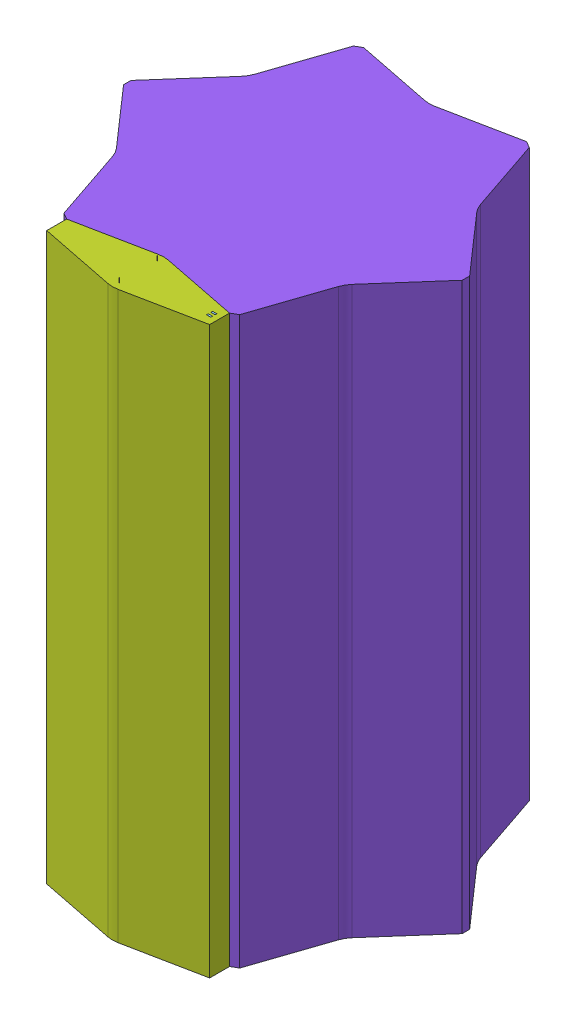
SolidWorks assembly String-Array, configuration 默认. Lengths in mm.
Overall size (790 1330.46 891.35).
243 component instances, 8 part files, 4 mates.
Components (placement in the parent):
- RealString-1: RealString [默认] at (506.9717 -579.0791 1993.5225) size (380 1330.46 350.65)
  - RealUnit-1: RealUnit [默认] at origin size (374.87 90.61 350.65)
    - BEGeDet-1: BEGeDet [默认] at (2.9686 -23.0613 80) size (80 40 80)
    - InnerShell-IV-1: InnerShell-IV [默认] at (2.9686 -23.1113 80) x (0.656103 0 0.754671) z (-0.754671 0 0.656103) size (90 50 90)
    - RealOuterShell-IV-Part-3: RealOuterShell-IV-Part [默认] at (2.9686 -24.1113 80) x (-1 0 0) z (0 0 -1) size (357.21 73.56 262.25)
    - RealOuterShell-IV-Part-4: RealOuterShell-IV-Part [默认] at (2.5967 -24.1114 80) x (1 0.000332 0) z (0 0 1) size (357.21 73.56 262.25)
    - Electronics-1: Electronics [默认] at (2.9686 -48.2113 80) x (-1 0 0) z (0 0 -1) size (21.21 85 89.7)
    - ConnectionUnit-1: ConnectionUnit [默认] at (157.8605 -24.8554 155) x (-1 -0.000332 0) z (0 0 -1) size (23 75 26.4)
      - ConnectionRod-IV-1: ConnectionRod-IV [默认] at (-16.742 6.238 75) size (23 75 14)
      - RealSiPMArray-1: RealSiPMArray [默认] at (-11.242 1.238 75) x (-1 0 0) z (0 0 -1) size (3.97 70 26.4)
    - ConnectionUnit-2: ConnectionUnit [默认] at (-152.295 -24.9069 5) size (23 75 26.4)
      - ConnectionRod-IV-1: ConnectionRod-IV [默认] at (-16.742 6.238 75) size (23 75 14)
      - RealSiPMArray-1: RealSiPMArray [默认] at (-11.242 1.238 75) x (-1 0 0) z (0 0 -1) size (3.97 70 26.4)
  - RealUnit-2: RealUnit [默认] at (0 65 0) size (374.87 90.61 350.65)
    - BEGeDet-1: BEGeDet [默认] at (2.9686 -23.0613 80) size (80 40 80)
    - InnerShell-IV-1: InnerShell-IV [默认] at (2.9686 -23.1113 80) x (0.656103 0 0.754671) z (-0.754671 0 0.656103) size (90 50 90)
    - RealOuterShell-IV-Part-3: RealOuterShell-IV-Part [默认] at (2.9686 -24.1113 80) x (-1 0 0) z (0 0 -1) size (357.21 73.56 262.25)
    - RealOuterShell-IV-Part-4: RealOuterShell-IV-Part [默认] at (2.5967 -24.1114 80) x (1 0.000332 0) z (0 0 1) size (357.21 73.56 262.25)
    - Electronics-1: Electronics [默认] at (2.9686 -48.2113 80) x (-1 0 0) z (0 0 -1) size (21.21 85 89.7)
    - ConnectionUnit-1: ConnectionUnit [默认] at (157.8605 -24.8554 155) x (-1 -0.000332 0) z (0 0 -1) size (23 75 26.4)
      - ConnectionRod-IV-1: ConnectionRod-IV [默认] at (-16.742 6.238 75) size (23 75 14)
      - RealSiPMArray-1: RealSiPMArray [默认] at (-11.242 1.238 75) x (-1 0 0) z (0 0 -1) size (3.97 70 26.4)
    - ConnectionUnit-2: ConnectionUnit [默认] at (-152.295 -24.9069 5) size (23 75 26.4)
      - ConnectionRod-IV-1: ConnectionRod-IV [默认] at (-16.742 6.238 75) size (23 75 14)
      - RealSiPMArray-1: RealSiPMArray [默认] at (-11.242 1.238 75) x (-1 0 0) z (0 0 -1) size (3.97 70 26.4)
  - RealUnit-3: RealUnit [默认] at (0 130 0) size (374.87 90.61 350.65)
    - BEGeDet-1: BEGeDet [默认] at (2.9686 -23.0613 80) size (80 40 80)
    - InnerShell-IV-1: InnerShell-IV [默认] at (2.9686 -23.1113 80) x (0.656103 0 0.754671) z (-0.754671 0 0.656103) size (90 50 90)
    - RealOuterShell-IV-Part-3: RealOuterShell-IV-Part [默认] at (2.9686 -24.1113 80) x (-1 0 0) z (0 0 -1) size (357.21 73.56 262.25)
    - RealOuterShell-IV-Part-4: RealOuterShell-IV-Part [默认] at (2.5967 -24.1114 80) x (1 0.000332 0) z (0 0 1) size (357.21 73.56 262.25)
    - Electronics-1: Electronics [默认] at (2.9686 -48.2113 80) x (-1 0 0) z (0 0 -1) size (21.21 85 89.7)
    - ConnectionUnit-1: ConnectionUnit [默认] at (157.8605 -24.8554 155) x (-1 -0.000332 0) z (0 0 -1) size (23 75 26.4)
      - ConnectionRod-IV-1: ConnectionRod-IV [默认] at (-16.742 6.238 75) size (23 75 14)
      - RealSiPMArray-1: RealSiPMArray [默认] at (-11.242 1.238 75) x (-1 0 0) z (0 0 -1) size (3.97 70 26.4)
    - ConnectionUnit-2: ConnectionUnit [默认] at (-152.295 -24.9069 5) size (23 75 26.4)
      - ConnectionRod-IV-1: ConnectionRod-IV [默认] at (-16.742 6.238 75) size (23 75 14)
      - RealSiPMArray-1: RealSiPMArray [默认] at (-11.242 1.238 75) x (-1 0 0) z (0 0 -1) size (3.97 70 26.4)
  - RealUnit-4: RealUnit [默认] at (0 195 0) size (374.87 90.61 350.65)
    - BEGeDet-1: BEGeDet [默认] at (2.9686 -23.0613 80) size (80 40 80)
    - InnerShell-IV-1: InnerShell-IV [默认] at (2.9686 -23.1113 80) x (0.656103 0 0.754671) z (-0.754671 0 0.656103) size (90 50 90)
    - RealOuterShell-IV-Part-3: RealOuterShell-IV-Part [默认] at (2.9686 -24.1113 80) x (-1 0 0) z (0 0 -1) size (357.21 73.56 262.25)
    - RealOuterShell-IV-Part-4: RealOuterShell-IV-Part [默认] at (2.5967 -24.1114 80) x (1 0.000332 0) z (0 0 1) size (357.21 73.56 262.25)
    - Electronics-1: Electronics [默认] at (2.9686 -48.2113 80) x (-1 0 0) z (0 0 -1) size (21.21 85 89.7)
    - ConnectionUnit-1: ConnectionUnit [默认] at (157.8605 -24.8554 155) x (-1 -0.000332 0) z (0 0 -1) size (23 75 26.4)
      - ConnectionRod-IV-1: ConnectionRod-IV [默认] at (-16.742 6.238 75) size (23 75 14)
      - RealSiPMArray-1: RealSiPMArray [默认] at (-11.242 1.238 75) x (-1 0 0) z (0 0 -1) size (3.97 70 26.4)
    - ConnectionUnit-2: ConnectionUnit [默认] at (-152.295 -24.9069 5) size (23 75 26.4)
      - ConnectionRod-IV-1: ConnectionRod-IV [默认] at (-16.742 6.238 75) size (23 75 14)
      - RealSiPMArray-1: RealSiPMArray [默认] at (-11.242 1.238 75) x (-1 0 0) z (0 0 -1) size (3.97 70 26.4)
  - RealUnit-5: RealUnit [默认] at (0 260 0) size (374.87 90.61 350.65)
    - BEGeDet-1: BEGeDet [默认] at (2.9686 -23.0613 80) size (80 40 80)
    - InnerShell-IV-1: InnerShell-IV [默认] at (2.9686 -23.1113 80) x (0.656103 0 0.754671) z (-0.754671 0 0.656103) size (90 50 90)
    - RealOuterShell-IV-Part-3: RealOuterShell-IV-Part [默认] at (2.9686 -24.1113 80) x (-1 0 0) z (0 0 -1) size (357.21 73.56 262.25)
    - RealOuterShell-IV-Part-4: RealOuterShell-IV-Part [默认] at (2.5967 -24.1114 80) x (1 0.000332 0) z (0 0 1) size (357.21 73.56 262.25)
    - Electronics-1: Electronics [默认] at (2.9686 -48.2113 80) x (-1 0 0) z (0 0 -1) size (21.21 85 89.7)
    - ConnectionUnit-1: ConnectionUnit [默认] at (157.8605 -24.8554 155) x (-1 -0.000332 0) z (0 0 -1) size (23 75 26.4)
      - ConnectionRod-IV-1: ConnectionRod-IV [默认] at (-16.742 6.238 75) size (23 75 14)
      - RealSiPMArray-1: RealSiPMArray [默认] at (-11.242 1.238 75) x (-1 0 0) z (0 0 -1) size (3.97 70 26.4)
    - ConnectionUnit-2: ConnectionUnit [默认] at (-152.295 -24.9069 5) size (23 75 26.4)
      - ConnectionRod-IV-1: ConnectionRod-IV [默认] at (-16.742 6.238 75) size (23 75 14)
      - RealSiPMArray-1: RealSiPMArray [默认] at (-11.242 1.238 75) x (-1 0 0) z (0 0 -1) size (3.97 70 26.4)
  - RealUnit-6: RealUnit [默认] at (0 325 0) size (374.87 90.61 350.65)
    - BEGeDet-1: BEGeDet [默认] at (2.9686 -23.0613 80) size (80 40 80)
    - InnerShell-IV-1: InnerShell-IV [默认] at (2.9686 -23.1113 80) x (0.656103 0 0.754671) z (-0.754671 0 0.656103) size (90 50 90)
    - RealOuterShell-IV-Part-3: RealOuterShell-IV-Part [默认] at (2.9686 -24.1113 80) x (-1 0 0) z (0 0 -1) size (357.21 73.56 262.25)
    - RealOuterShell-IV-Part-4: RealOuterShell-IV-Part [默认] at (2.5967 -24.1114 80) x (1 0.000332 0) z (0 0 1) size (357.21 73.56 262.25)
    - Electronics-1: Electronics [默认] at (2.9686 -48.2113 80) x (-1 0 0) z (0 0 -1) size (21.21 85 89.7)
    - ConnectionUnit-1: ConnectionUnit [默认] at (157.8605 -24.8554 155) x (-1 -0.000332 0) z (0 0 -1) size (23 75 26.4)
      - ConnectionRod-IV-1: ConnectionRod-IV [默认] at (-16.742 6.238 75) size (23 75 14)
      - RealSiPMArray-1: RealSiPMArray [默认] at (-11.242 1.238 75) x (-1 0 0) z (0 0 -1) size (3.97 70 26.4)
    - ConnectionUnit-2: ConnectionUnit [默认] at (-152.295 -24.9069 5) size (23 75 26.4)
      - ConnectionRod-IV-1: ConnectionRod-IV [默认] at (-16.742 6.238 75) size (23 75 14)
      - RealSiPMArray-1: RealSiPMArray [默认] at (-11.242 1.238 75) x (-1 0 0) z (0 0 -1) size (3.97 70 26.4)
  - RealUnit-7: RealUnit [默认] at (0 390 0) size (374.87 90.61 350.65)
    - BEGeDet-1: BEGeDet [默认] at (2.9686 -23.0613 80) size (80 40 80)
    - InnerShell-IV-1: InnerShell-IV [默认] at (2.9686 -23.1113 80) x (0.656103 0 0.754671) z (-0.754671 0 0.656103) size (90 50 90)
    - RealOuterShell-IV-Part-3: RealOuterShell-IV-Part [默认] at (2.9686 -24.1113 80) x (-1 0 0) z (0 0 -1) size (357.21 73.56 262.25)
    - RealOuterShell-IV-Part-4: RealOuterShell-IV-Part [默认] at (2.5967 -24.1114 80) x (1 0.000332 0) z (0 0 1) size (357.21 73.56 262.25)
    - Electronics-1: Electronics [默认] at (2.9686 -48.2113 80) x (-1 0 0) z (0 0 -1) size (21.21 85 89.7)
    - ConnectionUnit-1: ConnectionUnit [默认] at (157.8605 -24.8554 155) x (-1 -0.000332 0) z (0 0 -1) size (23 75 26.4)
      - ConnectionRod-IV-1: ConnectionRod-IV [默认] at (-16.742 6.238 75) size (23 75 14)
      - RealSiPMArray-1: RealSiPMArray [默认] at (-11.242 1.238 75) x (-1 0 0) z (0 0 -1) size (3.97 70 26.4)
    - ConnectionUnit-2: ConnectionUnit [默认] at (-152.295 -24.9069 5) size (23 75 26.4)
      - ConnectionRod-IV-1: ConnectionRod-IV [默认] at (-16.742 6.238 75) size (23 75 14)
      - RealSiPMArray-1: RealSiPMArray [默认] at (-11.242 1.238 75) x (-1 0 0) z (0 0 -1) size (3.97 70 26.4)
  - RealUnit-8: RealUnit [默认] at (0 455 0) size (374.87 90.61 350.65)
    - BEGeDet-1: BEGeDet [默认] at (2.9686 -23.0613 80) size (80 40 80)
    - InnerShell-IV-1: InnerShell-IV [默认] at (2.9686 -23.1113 80) x (0.656103 0 0.754671) z (-0.754671 0 0.656103) size (90 50 90)
    - RealOuterShell-IV-Part-3: RealOuterShell-IV-Part [默认] at (2.9686 -24.1113 80) x (-1 0 0) z (0 0 -1) size (357.21 73.56 262.25)
    - RealOuterShell-IV-Part-4: RealOuterShell-IV-Part [默认] at (2.5967 -24.1114 80) x (1 0.000332 0) z (0 0 1) size (357.21 73.56 262.25)
    - Electronics-1: Electronics [默认] at (2.9686 -48.2113 80) x (-1 0 0) z (0 0 -1) size (21.21 85 89.7)
    - ConnectionUnit-1: ConnectionUnit [默认] at (157.8605 -24.8554 155) x (-1 -0.000332 0) z (0 0 -1) size (23 75 26.4)
      - ConnectionRod-IV-1: ConnectionRod-IV [默认] at (-16.742 6.238 75) size (23 75 14)
      - RealSiPMArray-1: RealSiPMArray [默认] at (-11.242 1.238 75) x (-1 0 0) z (0 0 -1) size (3.97 70 26.4)
    - ConnectionUnit-2: ConnectionUnit [默认] at (-152.295 -24.9069 5) size (23 75 26.4)
      - ConnectionRod-IV-1: ConnectionRod-IV [默认] at (-16.742 6.238 75) size (23 75 14)
      - RealSiPMArray-1: RealSiPMArray [默认] at (-11.242 1.238 75) x (-1 0 0) z (0 0 -1) size (3.97 70 26.4)
  - RealUnit-9: RealUnit [默认] at (0 520 0) size (374.87 90.61 350.65)
    - BEGeDet-1: BEGeDet [默认] at (2.9686 -23.0613 80) size (80 40 80)
    - InnerShell-IV-1: InnerShell-IV [默认] at (2.9686 -23.1113 80) x (0.656103 0 0.754671) z (-0.754671 0 0.656103) size (90 50 90)
    - RealOuterShell-IV-Part-3: RealOuterShell-IV-Part [默认] at (2.9686 -24.1113 80) x (-1 0 0) z (0 0 -1) size (357.21 73.56 262.25)
    - RealOuterShell-IV-Part-4: RealOuterShell-IV-Part [默认] at (2.5967 -24.1114 80) x (1 0.000332 0) z (0 0 1) size (357.21 73.56 262.25)
    - Electronics-1: Electronics [默认] at (2.9686 -48.2113 80) x (-1 0 0) z (0 0 -1) size (21.21 85 89.7)
    - ConnectionUnit-1: ConnectionUnit [默认] at (157.8605 -24.8554 155) x (-1 -0.000332 0) z (0 0 -1) size (23 75 26.4)
      - ConnectionRod-IV-1: ConnectionRod-IV [默认] at (-16.742 6.238 75) size (23 75 14)
      - RealSiPMArray-1: RealSiPMArray [默认] at (-11.242 1.238 75) x (-1 0 0) z (0 0 -1) size (3.97 70 26.4)
    - ConnectionUnit-2: ConnectionUnit [默认] at (-152.295 -24.9069 5) size (23 75 26.4)
      - ConnectionRod-IV-1: ConnectionRod-IV [默认] at (-16.742 6.238 75) size (23 75 14)
      - RealSiPMArray-1: RealSiPMArray [默认] at (-11.242 1.238 75) x (-1 0 0) z (0 0 -1) size (3.97 70 26.4)
  - RealUnit-10: RealUnit [默认] at (0 585 0) size (374.87 90.61 350.65)
    - BEGeDet-1: BEGeDet [默认] at (2.9686 -23.0613 80) size (80 40 80)
    - InnerShell-IV-1: InnerShell-IV [默认] at (2.9686 -23.1113 80) x (0.656103 0 0.754671) z (-0.754671 0 0.656103) size (90 50 90)
    - RealOuterShell-IV-Part-3: RealOuterShell-IV-Part [默认] at (2.9686 -24.1113 80) x (-1 0 0) z (0 0 -1) size (357.21 73.56 262.25)
    - RealOuterShell-IV-Part-4: RealOuterShell-IV-Part [默认] at (2.5967 -24.1114 80) x (1 0.000332 0) z (0 0 1) size (357.21 73.56 262.25)
    - Electronics-1: Electronics [默认] at (2.9686 -48.2113 80) x (-1 0 0) z (0 0 -1) size (21.21 85 89.7)
    - ConnectionUnit-1: ConnectionUnit [默认] at (157.8605 -24.8554 155) x (-1 -0.000332 0) z (0 0 -1) size (23 75 26.4)
      - ConnectionRod-IV-1: ConnectionRod-IV [默认] at (-16.742 6.238 75) size (23 75 14)
      - RealSiPMArray-1: RealSiPMArray [默认] at (-11.242 1.238 75) x (-1 0 0) z (0 0 -1) size (3.97 70 26.4)
    - ConnectionUnit-2: ConnectionUnit [默认] at (-152.295 -24.9069 5) size (23 75 26.4)
      - ConnectionRod-IV-1: ConnectionRod-IV [默认] at (-16.742 6.238 75) size (23 75 14)
      - RealSiPMArray-1: RealSiPMArray [默认] at (-11.242 1.238 75) x (-1 0 0) z (0 0 -1) size (3.97 70 26.4)
  - RealUnit-11: RealUnit [默认] at (0 650 0) size (374.87 90.61 350.65)
    - BEGeDet-1: BEGeDet [默认] at (2.9686 -23.0613 80) size (80 40 80)
    - InnerShell-IV-1: InnerShell-IV [默认] at (2.9686 -23.1113 80) x (0.656103 0 0.754671) z (-0.754671 0 0.656103) size (90 50 90)
    - RealOuterShell-IV-Part-3: RealOuterShell-IV-Part [默认] at (2.9686 -24.1113 80) x (-1 0 0) z (0 0 -1) size (357.21 73.56 262.25)
    - RealOuterShell-IV-Part-4: RealOuterShell-IV-Part [默认] at (2.5967 -24.1114 80) x (1 0.000332 0) z (0 0 1) size (357.21 73.56 262.25)
    - Electronics-1: Electronics [默认] at (2.9686 -48.2113 80) x (-1 0 0) z (0 0 -1) size (21.21 85 89.7)
    - ConnectionUnit-1: ConnectionUnit [默认] at (157.8605 -24.8554 155) x (-1 -0.000332 0) z (0 0 -1) size (23 75 26.4)
      - ConnectionRod-IV-1: ConnectionRod-IV [默认] at (-16.742 6.238 75) size (23 75 14)
      - RealSiPMArray-1: RealSiPMArray [默认] at (-11.242 1.238 75) x (-1 0 0) z (0 0 -1) size (3.97 70 26.4)
    - ConnectionUnit-2: ConnectionUnit [默认] at (-152.295 -24.9069 5) size (23 75 26.4)
      - ConnectionRod-IV-1: ConnectionRod-IV [默认] at (-16.742 6.238 75) size (23 75 14)
      - RealSiPMArray-1: RealSiPMArray [默认] at (-11.242 1.238 75) x (-1 0 0) z (0 0 -1) size (3.97 70 26.4)
  - RealUnit-12: RealUnit [默认] at (0 715 0) size (374.87 90.61 350.65)
    - BEGeDet-1: BEGeDet [默认] at (2.9686 -23.0613 80) size (80 40 80)
    - InnerShell-IV-1: InnerShell-IV [默认] at (2.9686 -23.1113 80) x (0.656103 0 0.754671) z (-0.754671 0 0.656103) size (90 50 90)
    - RealOuterShell-IV-Part-3: RealOuterShell-IV-Part [默认] at (2.9686 -24.1113 80) x (-1 0 0) z (0 0 -1) size (357.21 73.56 262.25)
    - RealOuterShell-IV-Part-4: RealOuterShell-IV-Part [默认] at (2.5967 -24.1114 80) x (1 0.000332 0) z (0 0 1) size (357.21 73.56 262.25)
    - Electronics-1: Electronics [默认] at (2.9686 -48.2113 80) x (-1 0 0) z (0 0 -1) size (21.21 85 89.7)
    - ConnectionUnit-1: ConnectionUnit [默认] at (157.8605 -24.8554 155) x (-1 -0.000332 0) z (0 0 -1) size (23 75 26.4)
      - ConnectionRod-IV-1: ConnectionRod-IV [默认] at (-16.742 6.238 75) size (23 75 14)
      - RealSiPMArray-1: RealSiPMArray [默认] at (-11.242 1.238 75) x (-1 0 0) z (0 0 -1) size (3.97 70 26.4)
    - ConnectionUnit-2: ConnectionUnit [默认] at (-152.295 -24.9069 5) size (23 75 26.4)
      - ConnectionRod-IV-1: ConnectionRod-IV [默认] at (-16.742 6.238 75) size (23 75 14)
      - RealSiPMArray-1: RealSiPMArray [默认] at (-11.242 1.238 75) x (-1 0 0) z (0 0 -1) size (3.97 70 26.4)
  - RealUnit-13: RealUnit [默认] at (0 780 0) size (374.87 90.61 350.65)
    - BEGeDet-1: BEGeDet [默认] at (2.9686 -23.0613 80) size (80 40 80)
    - InnerShell-IV-1: InnerShell-IV [默认] at (2.9686 -23.1113 80) x (0.656103 0 0.754671) z (-0.754671 0 0.656103) size (90 50 90)
    - RealOuterShell-IV-Part-3: RealOuterShell-IV-Part [默认] at (2.9686 -24.1113 80) x (-1 0 0) z (0 0 -1) size (357.21 73.56 262.25)
    - RealOuterShell-IV-Part-4: RealOuterShell-IV-Part [默认] at (2.5967 -24.1114 80) x (1 0.000332 0) z (0 0 1) size (357.21 73.56 262.25)
    - Electronics-1: Electronics [默认] at (2.9686 -48.2113 80) x (-1 0 0) z (0 0 -1) size (21.21 85 89.7)
    - ConnectionUnit-1: ConnectionUnit [默认] at (157.8605 -24.8554 155) x (-1 -0.000332 0) z (0 0 -1) size (23 75 26.4)
      - ConnectionRod-IV-1: ConnectionRod-IV [默认] at (-16.742 6.238 75) size (23 75 14)
      - RealSiPMArray-1: RealSiPMArray [默认] at (-11.242 1.238 75) x (-1 0 0) z (0 0 -1) size (3.97 70 26.4)
    - ConnectionUnit-2: ConnectionUnit [默认] at (-152.295 -24.9069 5) size (23 75 26.4)
      - ConnectionRod-IV-1: ConnectionRod-IV [默认] at (-16.742 6.238 75) size (23 75 14)
      - RealSiPMArray-1: RealSiPMArray [默认] at (-11.242 1.238 75) x (-1 0 0) z (0 0 -1) size (3.97 70 26.4)
  - RealUnit-14: RealUnit [默认] at (0 845 0) size (374.87 90.61 350.65)
    - BEGeDet-1: BEGeDet [默认] at (2.9686 -23.0613 80) size (80 40 80)
    - InnerShell-IV-1: InnerShell-IV [默认] at (2.9686 -23.1113 80) x (0.656103 0 0.754671) z (-0.754671 0 0.656103) size (90 50 90)
    - RealOuterShell-IV-Part-3: RealOuterShell-IV-Part [默认] at (2.9686 -24.1113 80) x (-1 0 0) z (0 0 -1) size (357.21 73.56 262.25)
    - RealOuterShell-IV-Part-4: RealOuterShell-IV-Part [默认] at (2.5967 -24.1114 80) x (1 0.000332 0) z (0 0 1) size (357.21 73.56 262.25)
    - Electronics-1: Electronics [默认] at (2.9686 -48.2113 80) x (-1 0 0) z (0 0 -1) size (21.21 85 89.7)
    - ConnectionUnit-1: ConnectionUnit [默认] at (157.8605 -24.8554 155) x (-1 -0.000332 0) z (0 0 -1) size (23 75 26.4)
      - ConnectionRod-IV-1: ConnectionRod-IV [默认] at (-16.742 6.238 75) size (23 75 14)
      - RealSiPMArray-1: RealSiPMArray [默认] at (-11.242 1.238 75) x (-1 0 0) z (0 0 -1) size (3.97 70 26.4)
    - ConnectionUnit-2: ConnectionUnit [默认] at (-152.295 -24.9069 5) size (23 75 26.4)
      - ConnectionRod-IV-1: ConnectionRod-IV [默认] at (-16.742 6.238 75) size (23 75 14)
      - RealSiPMArray-1: RealSiPMArray [默认] at (-11.242 1.238 75) x (-1 0 0) z (0 0 -1) size (3.97 70 26.4)
  - RealUnit-15: RealUnit [默认] at (0 910 0) size (374.87 90.61 350.65)
    - BEGeDet-1: BEGeDet [默认] at (2.9686 -23.0613 80) size (80 40 80)
    - InnerShell-IV-1: InnerShell-IV [默认] at (2.9686 -23.1113 80) x (0.656103 0 0.754671) z (-0.754671 0 0.656103) size (90 50 90)
    - RealOuterShell-IV-Part-3: RealOuterShell-IV-Part [默认] at (2.9686 -24.1113 80) x (-1 0 0) z (0 0 -1) size (357.21 73.56 262.25)
    - RealOuterShell-IV-Part-4: RealOuterShell-IV-Part [默认] at (2.5967 -24.1114 80) x (1 0.000332 0) z (0 0 1) size (357.21 73.56 262.25)
    - Electronics-1: Electronics [默认] at (2.9686 -48.2113 80) x (-1 0 0) z (0 0 -1) size (21.21 85 89.7)
    - ConnectionUnit-1: ConnectionUnit [默认] at (157.8605 -24.8554 155) x (-1 -0.000332 0) z (0 0 -1) size (23 75 26.4)
      - ConnectionRod-IV-1: ConnectionRod-IV [默认] at (-16.742 6.238 75) size (23 75 14)
      - RealSiPMArray-1: RealSiPMArray [默认] at (-11.242 1.238 75) x (-1 0 0) z (0 0 -1) size (3.97 70 26.4)
    - ConnectionUnit-2: ConnectionUnit [默认] at (-152.295 -24.9069 5) size (23 75 26.4)
      - ConnectionRod-IV-1: ConnectionRod-IV [默认] at (-16.742 6.238 75) size (23 75 14)
      - RealSiPMArray-1: RealSiPMArray [默认] at (-11.242 1.238 75) x (-1 0 0) z (0 0 -1) size (3.97 70 26.4)
  - RealUnit-16: RealUnit [默认] at (0 975 0) size (374.87 90.61 350.65)
    - BEGeDet-1: BEGeDet [默认] at (2.9686 -23.0613 80) size (80 40 80)
    - InnerShell-IV-1: InnerShell-IV [默认] at (2.9686 -23.1113 80) x (0.656103 0 0.754671) z (-0.754671 0 0.656103) size (90 50 90)
    - RealOuterShell-IV-Part-3: RealOuterShell-IV-Part [默认] at (2.9686 -24.1113 80) x (-1 0 0) z (0 0 -1) size (357.21 73.56 262.25)
    - RealOuterShell-IV-Part-4: RealOuterShell-IV-Part [默认] at (2.5967 -24.1114 80) x (1 0.000332 0) z (0 0 1) size (357.21 73.56 262.25)
    - Electronics-1: Electronics [默认] at (2.9686 -48.2113 80) x (-1 0 0) z (0 0 -1) size (21.21 85 89.7)
    - ConnectionUnit-1: ConnectionUnit [默认] at (157.8605 -24.8554 155) x (-1 -0.000332 0) z (0 0 -1) size (23 75 26.4)
      - ConnectionRod-IV-1: ConnectionRod-IV [默认] at (-16.742 6.238 75) size (23 75 14)
      - RealSiPMArray-1: RealSiPMArray [默认] at (-11.242 1.238 75) x (-1 0 0) z (0 0 -1) size (3.97 70 26.4)
    - ConnectionUnit-2: ConnectionUnit [默认] at (-152.295 -24.9069 5) size (23 75 26.4)
      - ConnectionRod-IV-1: ConnectionRod-IV [默认] at (-16.742 6.238 75) size (23 75 14)
      - RealSiPMArray-1: RealSiPMArray [默认] at (-11.242 1.238 75) x (-1 0 0) z (0 0 -1) size (3.97 70 26.4)
  - RealUnit-17: RealUnit [默认] at (0 1040 0) size (374.87 90.61 350.65)
    - BEGeDet-1: BEGeDet [默认] at (2.9686 -23.0613 80) size (80 40 80)
    - InnerShell-IV-1: InnerShell-IV [默认] at (2.9686 -23.1113 80) x (0.656103 0 0.754671) z (-0.754671 0 0.656103) size (90 50 90)
    - RealOuterShell-IV-Part-3: RealOuterShell-IV-Part [默认] at (2.9686 -24.1113 80) x (-1 0 0) z (0 0 -1) size (357.21 73.56 262.25)
    - RealOuterShell-IV-Part-4: RealOuterShell-IV-Part [默认] at (2.5967 -24.1114 80) x (1 0.000332 0) z (0 0 1) size (357.21 73.56 262.25)
    - Electronics-1: Electronics [默认] at (2.9686 -48.2113 80) x (-1 0 0) z (0 0 -1) size (21.21 85 89.7)
    - ConnectionUnit-1: ConnectionUnit [默认] at (157.8605 -24.8554 155) x (-1 -0.000332 0) z (0 0 -1) size (23 75 26.4)
      - ConnectionRod-IV-1: ConnectionRod-IV [默认] at (-16.742 6.238 75) size (23 75 14)
      - RealSiPMArray-1: RealSiPMArray [默认] at (-11.242 1.238 75) x (-1 0 0) z (0 0 -1) size (3.97 70 26.4)
    - ConnectionUnit-2: ConnectionUnit [默认] at (-152.295 -24.9069 5) size (23 75 26.4)
      - ConnectionRod-IV-1: ConnectionRod-IV [默认] at (-16.742 6.238 75) size (23 75 14)
      - RealSiPMArray-1: RealSiPMArray [默认] at (-11.242 1.238 75) x (-1 0 0) z (0 0 -1) size (3.97 70 26.4)
  - RealUnit-18: RealUnit [默认] at (0 1105 0) size (374.87 90.61 350.65)
    - BEGeDet-1: BEGeDet [默认] at (2.9686 -23.0613 80) size (80 40 80)
    - InnerShell-IV-1: InnerShell-IV [默认] at (2.9686 -23.1113 80) x (0.656103 0 0.754671) z (-0.754671 0 0.656103) size (90 50 90)
    - RealOuterShell-IV-Part-3: RealOuterShell-IV-Part [默认] at (2.9686 -24.1113 80) x (-1 0 0) z (0 0 -1) size (357.21 73.56 262.25)
    - RealOuterShell-IV-Part-4: RealOuterShell-IV-Part [默认] at (2.5967 -24.1114 80) x (1 0.000332 0) z (0 0 1) size (357.21 73.56 262.25)
    - Electronics-1: Electronics [默认] at (2.9686 -48.2113 80) x (-1 0 0) z (0 0 -1) size (21.21 85 89.7)
    - ConnectionUnit-1: ConnectionUnit [默认] at (157.8605 -24.8554 155) x (-1 -0.000332 0) z (0 0 -1) size (23 75 26.4)
      - ConnectionRod-IV-1: ConnectionRod-IV [默认] at (-16.742 6.238 75) size (23 75 14)
      - RealSiPMArray-1: RealSiPMArray [默认] at (-11.242 1.238 75) x (-1 0 0) z (0 0 -1) size (3.97 70 26.4)
    - ConnectionUnit-2: ConnectionUnit [默认] at (-152.295 -24.9069 5) size (23 75 26.4)
      - ConnectionRod-IV-1: ConnectionRod-IV [默认] at (-16.742 6.238 75) size (23 75 14)
      - RealSiPMArray-1: RealSiPMArray [默认] at (-11.242 1.238 75) x (-1 0 0) z (0 0 -1) size (3.97 70 26.4)
  - RealUnit-19: RealUnit [默认] at (0 1170 0) size (374.87 90.61 350.65)
    - BEGeDet-1: BEGeDet [默认] at (2.9686 -23.0613 80) size (80 40 80)
    - InnerShell-IV-1: InnerShell-IV [默认] at (2.9686 -23.1113 80) x (0.656103 0 0.754671) z (-0.754671 0 0.656103) size (90 50 90)
    - RealOuterShell-IV-Part-3: RealOuterShell-IV-Part [默认] at (2.9686 -24.1113 80) x (-1 0 0) z (0 0 -1) size (357.21 73.56 262.25)
    - RealOuterShell-IV-Part-4: RealOuterShell-IV-Part [默认] at (2.5967 -24.1114 80) x (1 0.000332 0) z (0 0 1) size (357.21 73.56 262.25)
    - Electronics-1: Electronics [默认] at (2.9686 -48.2113 80) x (-1 0 0) z (0 0 -1) size (21.21 85 89.7)
    - ConnectionUnit-1: ConnectionUnit [默认] at (157.8605 -24.8554 155) x (-1 -0.000332 0) z (0 0 -1) size (23 75 26.4)
      - ConnectionRod-IV-1: ConnectionRod-IV [默认] at (-16.742 6.238 75) size (23 75 14)
      - RealSiPMArray-1: RealSiPMArray [默认] at (-11.242 1.238 75) x (-1 0 0) z (0 0 -1) size (3.97 70 26.4)
    - ConnectionUnit-2: ConnectionUnit [默认] at (-152.295 -24.9069 5) size (23 75 26.4)
      - ConnectionRod-IV-1: ConnectionRod-IV [默认] at (-16.742 6.238 75) size (23 75 14)
      - RealSiPMArray-1: RealSiPMArray [默认] at (-11.242 1.238 75) x (-1 0 0) z (0 0 -1) size (3.97 70 26.4)
  - RealUnit-20: RealUnit [默认] at (0 1235 0) size (374.87 90.61 350.65)
    - BEGeDet-1: BEGeDet [默认] at (2.9686 -23.0613 80) size (80 40 80)
    - InnerShell-IV-1: InnerShell-IV [默认] at (2.9686 -23.1113 80) x (0.656103 0 0.754671) z (-0.754671 0 0.656103) size (90 50 90)
    - RealOuterShell-IV-Part-3: RealOuterShell-IV-Part [默认] at (2.9686 -24.1113 80) x (-1 0 0) z (0 0 -1) size (357.21 73.56 262.25)
    - RealOuterShell-IV-Part-4: RealOuterShell-IV-Part [默认] at (2.5967 -24.1114 80) x (1 0.000332 0) z (0 0 1) size (357.21 73.56 262.25)
    - Electronics-1: Electronics [默认] at (2.9686 -48.2113 80) x (-1 0 0) z (0 0 -1) size (21.21 85 89.7)
    - ConnectionUnit-1: ConnectionUnit [默认] at (157.8605 -24.8554 155) x (-1 -0.000332 0) z (0 0 -1) size (23 75 26.4)
      - ConnectionRod-IV-1: ConnectionRod-IV [默认] at (-16.742 6.238 75) size (23 75 14)
      - RealSiPMArray-1: RealSiPMArray [默认] at (-11.242 1.238 75) x (-1 0 0) z (0 0 -1) size (3.97 70 26.4)
    - ConnectionUnit-2: ConnectionUnit [默认] at (-152.295 -24.9069 5) size (23 75 26.4)
      - ConnectionRod-IV-1: ConnectionRod-IV [默认] at (-16.742 6.238 75) size (23 75 14)
      - RealSiPMArray-1: RealSiPMArray [默认] at (-11.242 1.238 75) x (-1 0 0) z (0 0 -1) size (3.97 70 26.4)
  - StringBox-IV-1: StringBox-IV [默认] at (2.9686 588.8311 80) size (380 1320 120)
- Container-IV-1: Container-IV [默认] at (509.9402 9.752 1703.9021) size (790 1320 692.82)
Mates (geometry in assembly coordinates):
- 重合1: coincident aligned: plane of RealString-1/StringBox-IV-1 through (509.9402 -650.248 2073.5225) normal (0 -1 0); plane of Container-IV-1 through (509.9402 -650.248 1703.9021) normal (0 -1 0)
- 重合3: coincident anti-aligned: plane of RealString-1/StringBox-IV-1 through (691.9002 659.752 2048.7053) normal (0.196 0 -0.980604); plane of Container-IV-1 through (699.9402 -650.248 2050.3123) normal (-0.196 0 0.980604)
- 重合4: coincident anti-aligned: plane of RealString-1/StringBox-IV-1 through (498.1802 659.752 2014.6863) normal (-0.196 0 -0.980604); plane of Container-IV-1 through (498.1802 -650.248 2014.6863) normal (0.196 0 0.980604)
- 同心1: concentric aligned: circle of RealString-1/RealUnit-20/InnerShell-IV-1; circle of Container-IV-1
